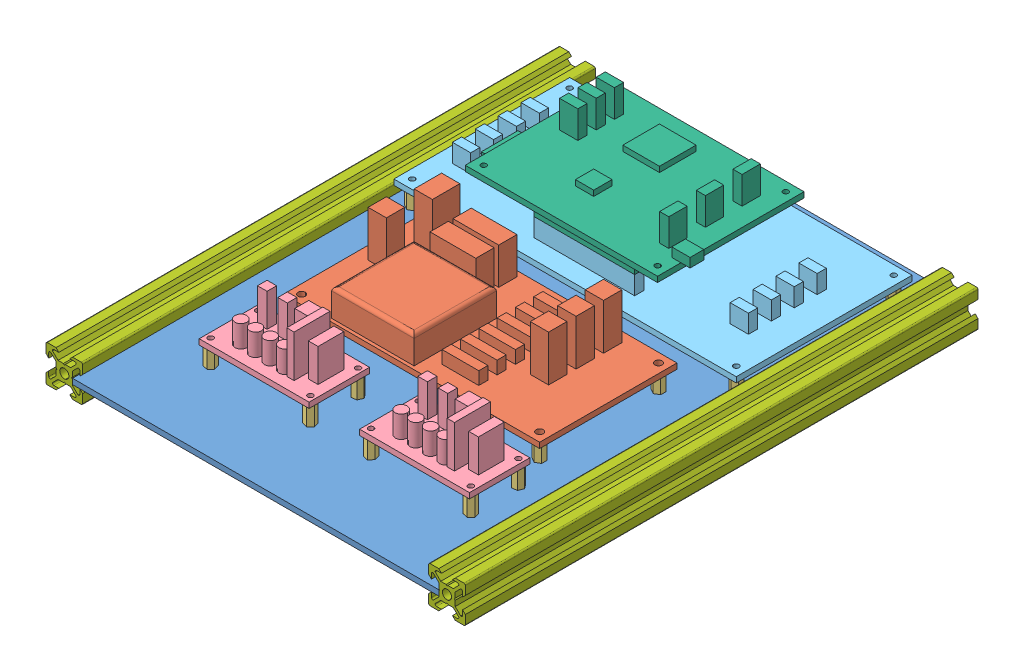
SolidWorks assembly Plaque_electronique, configuration Default. Lengths in mm.
Overall size (229 56 280).
28 component instances, 7 part files, 11 mates.
Components (placement in the parent):
- plaque_support_verticale_V1-1: plaque_support_verticale_V1 [Default] at (-127.9553 12.7512 108.9621) size (200 3 280)
- carte_puissance_2_entretoises-1: carte_puissance_2_entretoises [Default] at (-18.753 31.2662 -11.7793) size (140 38 75.52)
  - carte_puissance_2-1: carte_puissance_2 [Default] at (-78.4104 -5.515 36.4357) size (140 28 75.52)
  - entretoise_M3_L10-1: entretoise_M3_L10 [Default] at (-73.4104 -15.515 31.4357) size (5.2 10 6)
  - entretoise_M3_L10-2: entretoise_M3_L10 [Default] at (56.5896 -15.515 31.4357) size (5.2 10 6)
  - entretoise_M3_L10-3: entretoise_M3_L10 [Default] at (56.5896 -15.515 -33.5643) size (5.2 10 6)
  - entretoise_M3_L10-4: entretoise_M3_L10 [Default] at (-73.4104 -15.515 -33.5643) size (5.2 10 6)
- carte_hacheur_entretoise-1: carte_hacheur_entretoise [Default] at (-59.614 31.2845 52.2462) size (61.38 36 33.37)
  - carte_hacheur-1: carte_hacheur [Default] at (-39.4629 -5.5333 16.4207) size (60 26 33)
  - entretoise_M3_L10-1: entretoise_M3_L10 [Default] at (17.7871 -15.5333 -13.0793) x (0.923304 0 0.38407) z (-0.38407 0 0.923304) size (5.2 10 6)
  - entretoise_M3_L10-2: entretoise_M3_L10 [Default] at (17.7871 -15.5333 12.9207) x (0.960063 0 -0.279785) z (0.279785 0 0.960063) size (5.2 10 6)
  - entretoise_M3_L10-3: entretoise_M3_L10 [Default] at (-36.7129 -15.5333 12.9207) x (0.960063 0 -0.279785) z (0.279785 0 0.960063) size (5.2 10 6)
  - entretoise_M3_L10-4: entretoise_M3_L10 [Default] at (-36.7129 -15.5333 -13.0793) x (0.960063 0 -0.279785) z (0.279785 0 0.960063) size (5.2 10 6)
- carte_hacheur_entretoise-2: carte_hacheur_entretoise [Default] at (26.9677 31.2845 51.2353) size (61.38 36 33.37)
  - carte_hacheur-1: carte_hacheur [Default] at (-39.4629 -5.5333 16.4207) size (60 26 33)
  - entretoise_M3_L10-1: entretoise_M3_L10 [Default] at (17.7871 -15.5333 -13.0793) x (0.923304 0 0.38407) z (-0.38407 0 0.923304) size (5.2 10 6)
  - entretoise_M3_L10-2: entretoise_M3_L10 [Default] at (17.7871 -15.5333 12.9207) x (0.960063 0 -0.279785) z (0.279785 0 0.960063) size (5.2 10 6)
  - entretoise_M3_L10-3: entretoise_M3_L10 [Default] at (-36.7129 -15.5333 12.9207) x (0.960063 0 -0.279785) z (0.279785 0 0.960063) size (5.2 10 6)
  - entretoise_M3_L10-4: entretoise_M3_L10 [Default] at (-36.7129 -15.5333 -13.0793) x (0.960063 0 -0.279785) z (0.279785 0 0.960063) size (5.2 10 6)
- ensemble_carte_mere_IO_1-1: ensemble_carte_mere_IO_1 [Default] at (-10.2185 1.6412 -95.1806) size (187 46 96)
  - carte_interface_3-1: carte_interface_3 [Default] at (-111.2543 24.11 35.1427) size (187 13 96)
  - carte_PIC32_FPGA-1: carte_PIC32_FPGA [Default] at (-80.2543 42.11 27.1427) size (115 23 80)
  - entretoise_M3_L10-1: entretoise_M3_L10 [Default] at (-106.2543 14.11 -55.8573) size (5.2 10 6)
  - entretoise_M3_L10-2: entretoise_M3_L10 [Default] at (-106.2543 14.11 30.1427) size (5.2 10 6)
  - entretoise_M3_L10-3: entretoise_M3_L10 [Default] at (70.7457 14.11 -55.8573) size (5.2 10 6)
  - entretoise_M3_L10-4: entretoise_M3_L10 [Default] at (70.7457 14.11 30.1427) size (5.2 10 6)
- Profilé Aluminium Rexroth 20x20 L280-1: Profilé Aluminium Rexroth 20x20 L280 [Default] at (-132.4553 15.7512 -171.0379) x (1 0 0) z (0 -1 0) size (20 280 20)
- Profilé Aluminium Rexroth 20x20 L280-2: Profilé Aluminium Rexroth 20x20 L280 [Default] at (76.5447 15.7512 -171.0379) x (0 1 0) z (1 0 0) size (20 280 20)
Mates (geometry in assembly coordinates):
- Coïncidente1: coincident: plane of plaque_support_verticale_V1-1 through (-127.9553 15.7512 -171.0379) normal (0 1 0); plane of carte_puissance_2_entretoises-1/entretoise_M3_L10-4 through (-92.1634 15.7512 -48.3436) normal (0 -1 0)
- Coïncidente2: coincident: plane of plaque_support_verticale_V1-1 through (-127.9553 15.7512 -171.0379) normal (0 1 0); plane of ensemble_carte_mere_IO_1-1/entretoise_M3_L10-1 through (-116.4728 15.7512 -154.0379) normal (0 -1 0)
- Coïncidente3: coincident: plane of plaque_support_verticale_V1-1 through (-127.9553 15.7512 -171.0379) normal (0 1 0); plane of carte_hacheur_entretoise-1/entretoise_M3_L10-4 through (-97.1663 15.7512 36.2867) normal (0 -1 0)
- Coïncidente4: coincident: plane of plaque_support_verticale_V1-1 through (-127.9553 15.7512 -171.0379) normal (0 1 0); plane of carte_hacheur_entretoise-2/entretoise_M3_L10-3 through (-10.5845 15.7512 61.2758) normal (0 -1 0)
- Distance1: distance = 15 mm: plane of plaque_support_verticale_V1-1 through (-127.9553 15.7512 -171.0379) normal (0 0 -1); plane of ensemble_carte_mere_IO_1-1/carte_interface_3-1 through (-121.4728 28.7512 -156.0379) normal (0 0 -1)
- Coïncidente6: coincident: plane of plaque_support_verticale_V1-1 through (-127.9553 15.7512 -171.0379) normal (0 0 -1); plane of Profilé Aluminium Rexroth 20x20 L280-1 through (-132.4553 19.7512 -171.0379) normal (0 0 -1)
- Coïncidente7: coincident: plane of plaque_support_verticale_V1-1 through (-127.9553 15.7512 108.9621) normal (-1 0 0); plane of Profilé Aluminium Rexroth 20x20 L280-1 through (-127.9553 16.2512 108.9621) normal (1 0 0)
- Coïncidente8: coincident: plane of plaque_support_verticale_V1-1 through (-127.9553 12.7512 -171.0379) normal (0 -1 0); line of Profilé Aluminium Rexroth 20x20 L280-1
- Coïncidente9: coincident: plane of plaque_support_verticale_V1-1 through (72.0447 15.7512 108.9621) normal (1 0 0); plane of Profilé Aluminium Rexroth 20x20 L280-2 through (72.0447 15.2512 108.9621) normal (-1 0 0)
- Coïncidente10: coincident: plane of Profilé Aluminium Rexroth 20x20 L280-2 through (72.5447 15.7512 108.9621) normal (0 0 1); plane of plaque_support_verticale_V1-1 through (-127.9553 15.7512 108.9621) normal (0 0 1)
- Coïncidente12: coincident: plane of plaque_support_verticale_V1-1 through (-127.9553 12.7512 -171.0379) normal (0 -1 0); line of Profilé Aluminium Rexroth 20x20 L280-2
